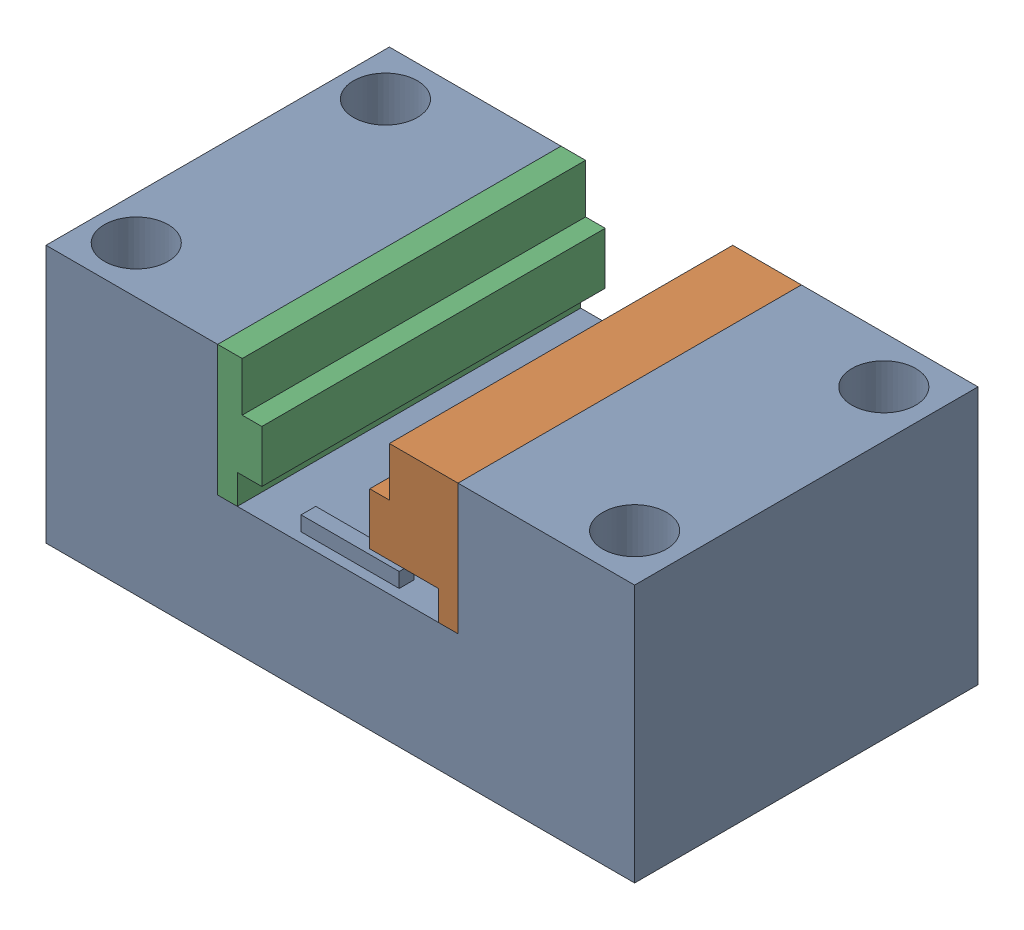
SolidWorks assembly TableAssembly, configuration Default. Lengths in mm.
Overall size (60 26.3 35).
2 component instances, 2 part files, 4 mates.
Components (placement in the parent):
- TableMount-1: TableMount [Default] at (29.0426 -11.1572 27.367) x (0 1 0) z (0 0 1) size (26.3 60 35)
- MoldHousing_11v3-2: MoldHousing_11v3 [Default] at (-1.2074 1.8428 -7.633) size (24.5 13.3 35)
Mates (geometry in assembly coordinates):
- Coincident1: coincident anti-aligned: plane of TableMount-1 through (-30.9574 1.8428 -7.633) normal (0 1 0); plane of MoldHousing_11v3-1 through (15.0893 1.8428 22.7559) normal (0 -1 0)
- Coincident2: coincident anti-aligned: plane of TableMount-1 through (-30.9574 1.8428 -7.633) normal (0 1 0); plane of MoldHousing_11v3-2 through (-13.4574 1.8428 27.367) normal (0 -1 0)
- Coincident3: coincident aligned: plane of TableMount-1 through (29.0426 -11.1572 27.367) normal (0 0 1); plane of MoldHousing_11v3-2 through (-1.2074 1.8428 27.367) normal (0 0 1)
- Distance1: distance = 5 mm anti-aligned: plane of MoldHousing_11v3-2 through (9.0426 1.8428 27.367) normal (-1 0 0); plane of TableMount-1 through (4.0426 3.3428 26.367) normal (1 0 0)
